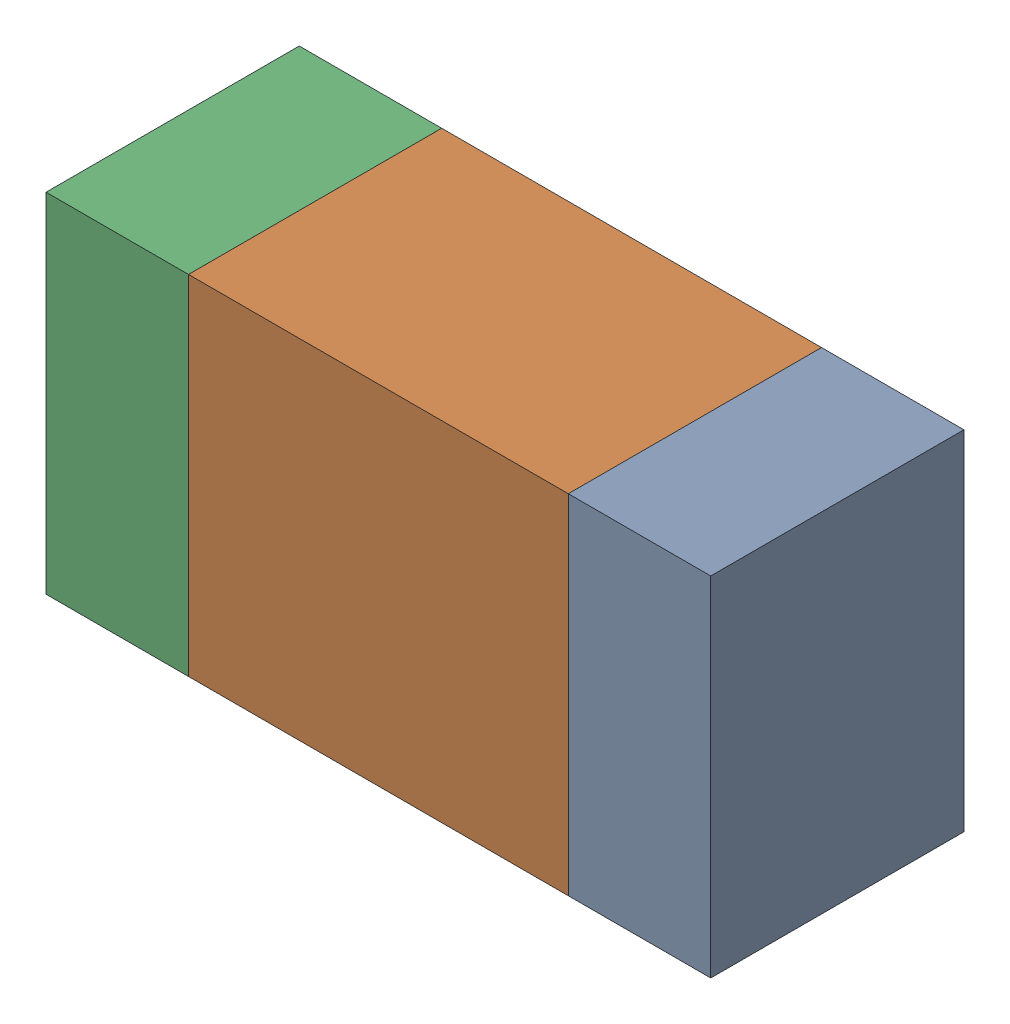
SolidWorks assembly R318_2PCB, configuration Default. Lengths in mm.
Overall size (1.05 0.55 0.4).
6 component instances, 2 part files, 0 mates.
Components (placement in the parent):
- 854785432-1: 854785432 [Default] at (136.0124 97.0001 -2.0638) size (0.22 0.55 0.4)
  - Extruded-1: Extruded [Default] at origin size (0.22 0.55 0.4)
- 854785568-1: 854785568 [Default] at (135.5999 97.0001 -2.0638) size (0.6 0.55 0.4)
  - Extruded_2-1: Extruded_2 [Default] at origin size (0.6 0.55 0.4)
- 854785432-2: 854785432 [Default] at (135.1874 97.0001 -2.0638) size (0.22 0.55 0.4)
  - Extruded-1: Extruded [Default] at origin size (0.22 0.55 0.4)
